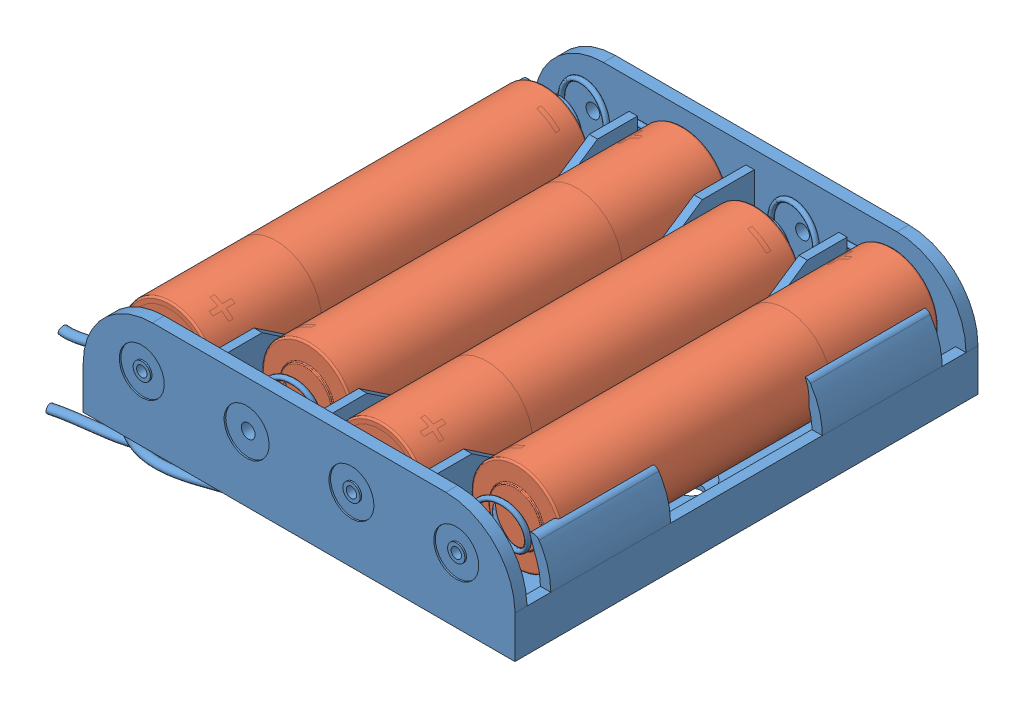
SolidWorks assembly 4x AAA Alkaline 1.5 V Battery Pack, configuration Default. Lengths in mm.
Overall size (54.8 18.32 52.2).
5 component instances, 2 part files, 0 mates.
Components (placement in the parent):
- BatteryPack4AAA-1: BatteryPack4AAA [Default] at origin size (54.34 16.46 52.2)
- AAABattery-1: AAABattery [Default] at (17.6964 8.2079 19.2636) x (-0.85083 -0.525441 0) z (0.525441 -0.85083 0) size (10.3 43.83 10.3)
- AAABattery-2: AAABattery [Default] at (-5.91 8.2079 19.2636) x (-0.85083 -0.525441 0) z (0.525441 -0.85083 0) size (10.3 43.83 10.3)
- AAABattery-3: AAABattery [Default] at (-17.6921 8.2079 -19.302) x (0.85083 -0.525441 0) z (-0.525441 -0.85083 0) size (10.3 43.83 10.3)
- AAABattery-4: AAABattery [Default] at (5.955 8.2079 -19.4197) x (0.85083 -0.525441 0) z (-0.525441 -0.85083 0) size (10.3 43.83 10.3)
